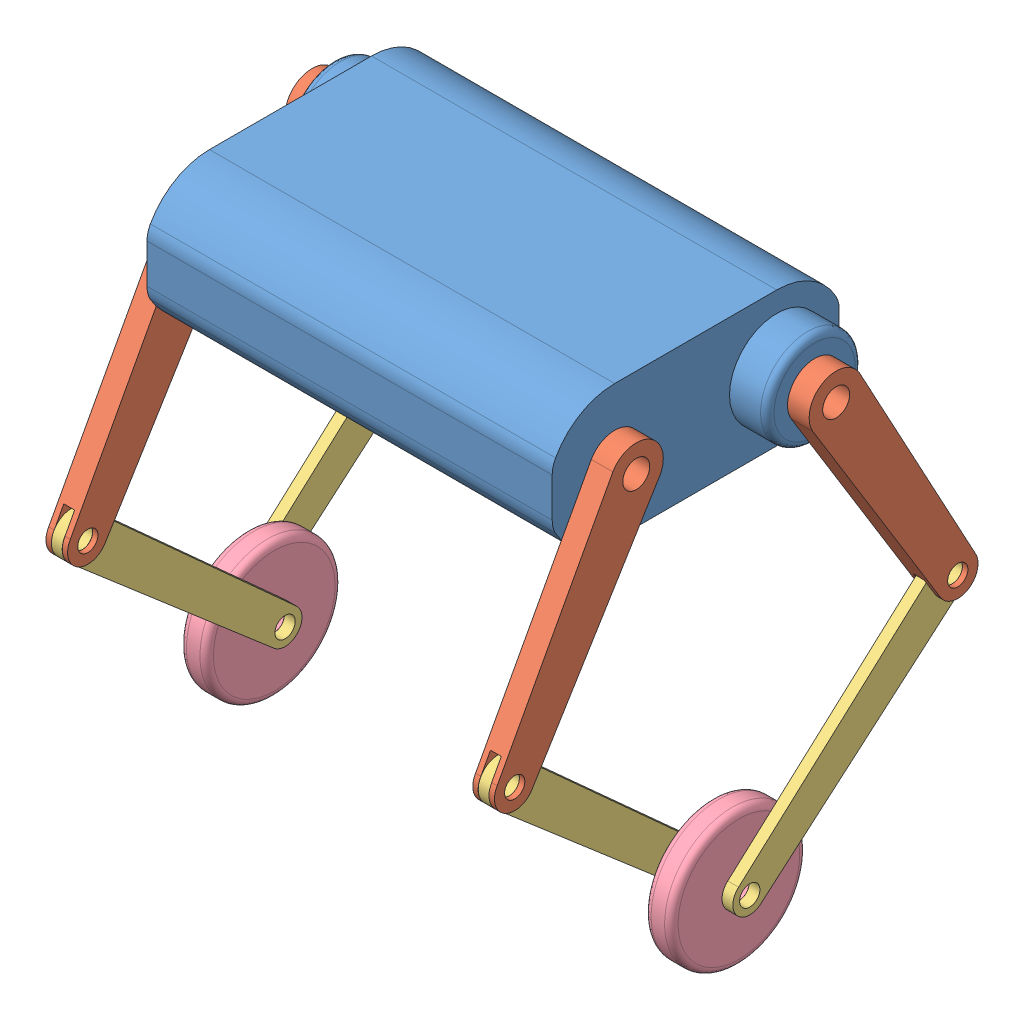
SolidWorks assembly 毕设轮足, configuration 默认. Lengths in mm.
Overall size (388 388.6 349.64).
12 component instances, 5 part files, 30 mates.
Components (placement in the parent):
- 机身-1: 机身 [默认] at (-112.6358 110.9969 -92.9782) size (356 100 212.5)
- 大腿-1: 大腿 [默认] at (187.3642 110.9969 -32.9782) x (1 0 0) z (0 0.5 0.866025) size (16 215 40)
- 大腿-2: 大腿 [默认] at (215.3642 110.9969 -152.9782) x (1 0 0) z (0 -0.5 0.866025) size (16 215 40)
- 小腿-1: 小腿 [默认] at (191.3642 -44.8877 57.0218) x (1 0 0) z (0 -0.75 0.661438) size (8 227.5 30)
- 小腿-2: 小腿 [默认] at (219.3642 -44.8877 -242.9782) x (1 0 0) z (0 0.75 0.661438) size (8 227.5 30)
- 车轮-1: 车轮 [默认] at (199.3642 -177.1752 -92.9782) x (1 0 0) z (0 -0.006127 0.999981) size (20 100 100)
- 大腿-3: 大腿 [默认] at (-112.6358 110.9969 -32.9782) x (-1 0 0) z (0 -0.5 -0.866025) size (16 215 40)
- 大腿-4: 大腿 [默认] at (-156.6358 110.9969 -152.9782) x (1 0 0) z (0 -0.5 0.866025) size (16 215 40)
- 小腿-3: 小腿 [默认] at (-116.6358 -44.8877 57.0218) x (-1 0 0) z (0 0.75 -0.661438) size (8 227.5 30)
- 小腿-4: 小腿 [默认] at (-144.6358 -44.8877 -242.9782) x (-1 0 0) z (0 -0.75 -0.661438) size (8 227.5 30)
- 车轮-2: 车轮 [默认] at (-124.6358 -177.1752 -92.9782) x (-1 0 0) z (0 0.999963 0.008584) size (20 100 100)
- 底板-1: 底板 [默认] at (37.3642 -247.1752 -92.9782) x (0 1 0) z (1 0 0) size (20 500 500) (hidden)
Mates (geometry in assembly coordinates):
- 重合1: coincident anti-aligned: plane of 机身-1 through (187.3642 110.9969 -92.9782) normal (1 0 0); plane of 大腿-1 through (187.3642 110.9969 -32.9782) normal (-1 0 0)
- 同心1: concentric anti-aligned: cylinder of 机身-1 through (187.3642 110.9969 -32.9782) axis (-1 0 0) radius 15; cylinder of 大腿-1 through (187.3642 110.9969 -32.9782) axis (1 0 0) radius 10
- 同心2: concentric anti-aligned: cylinder of 机身-1 through (187.3642 110.9969 -152.9782) axis (-1 0 0) radius 15; cylinder of 大腿-2 through (215.3642 110.9969 -152.9782) axis (1 0 0) radius 10
- 同心3: concentric aligned: cylinder of 大腿-1 through (187.3642 -44.8877 57.0218) axis (1 0 0) radius 7.5; cylinder of 小腿-1 through (189.3642 -44.8877 57.0218) axis (1 0 0) radius 7.5
- 宽度1: width aligned: plane of 大腿-1 through (203.3642 110.9969 -32.9782) normal (1 0 0); plane of 小腿-1 through (187.3642 110.9969 -32.9782) normal (-1 0 0); plane of 大腿-1 through (199.3642 -44.8877 57.0218) normal (1 0 0); plane of 小腿-1 through (191.3642 -44.8877 57.0218) normal (-1 0 0)
- 宽度2: width anti-aligned: plane of 大腿-2 through (231.3642 110.9969 -152.9782) normal (1 0 0); plane of 小腿-2 through (215.3642 110.9969 -152.9782) normal (-1 0 0); plane of 大腿-2 through (219.3642 -44.8877 -242.9782) normal (-1 0 0); plane of 小腿-2 through (227.3642 -44.8877 -242.9782) normal (1 0 0)
- 同心5: concentric aligned: cylinder of 大腿-2 through (215.3642 -44.8877 -242.9782) axis (1 0 0) radius 7.5; cylinder of 小腿-2 through (217.3642 -44.8877 -242.9782) axis (1 0 0) radius 7.5
- 距离1: distance = 20 mm anti-aligned: plane of 小腿-2 through (219.3642 -44.8877 -242.9782) normal (-1 0 0); plane of 小腿-1 through (199.3642 -44.8877 57.0218) normal (1 0 0)
- 同心6: concentric aligned: cylinder of 小腿-1 through (189.3642 -177.1752 -92.9782) axis (1 0 0) radius 7.5; cylinder of 小腿-2 through (217.3642 -177.1752 -92.9782) axis (1 0 0) radius 7.5
- 同心7: concentric anti-aligned: cylinder of 小腿-1 through (189.3642 -177.1752 -92.9782) axis (1 0 0) radius 7.5; cylinder of 车轮-1 through (219.3642 -177.1752 -92.9782) axis (-1 0 0) radius 50
- 重合2: coincident anti-aligned: plane of 小腿-1 through (199.3642 -44.8877 57.0218) normal (1 0 0); plane of 车轮-1 through (199.3642 -177.1752 -92.9782) normal (-1 0 0)
- 同心8: concentric aligned: cylinder of 大腿-3 through (-112.6358 -44.8877 57.0218) axis (-1 0 0) radius 7.5; cylinder of 小腿-3 through (-114.6358 -44.8877 57.0218) axis (-1 0 0) radius 7.5
- 宽度3: width aligned: plane of 大腿-3 through (-128.6358 110.9969 -32.9782) normal (-1 0 0); plane of 大腿-3 through (-112.6358 110.9969 -32.9782) normal (1 0 0); plane of 小腿-3 through (-124.6358 -44.8877 57.0218) normal (-1 0 0); plane of 小腿-3 through (-116.6358 -44.8877 57.0218) normal (1 0 0)
- 宽度4: width aligned: plane of 大腿-4 through (-140.6358 110.9969 -152.9782) normal (1 0 0); plane of 大腿-4 through (-156.6358 110.9969 -152.9782) normal (-1 0 0); plane of 小腿-4 through (-144.6358 -44.8877 -242.9782) normal (1 0 0); plane of 小腿-4 through (-152.6358 -44.8877 -242.9782) normal (-1 0 0)
- 同心9: concentric anti-aligned: cylinder of 大腿-4 through (-156.6358 -44.8877 -242.9782) axis (1 0 0) radius 7.5; cylinder of 小腿-4 through (-142.6358 -44.8877 -242.9782) axis (-1 0 0) radius 7.5
- 距离2: distance = 20 mm anti-aligned: plane of 小腿-4 through (-144.6358 -44.8877 -242.9782) normal (1 0 0); plane of 小腿-3 through (-124.6358 -44.8877 57.0218) normal (-1 0 0)
- 同心10: concentric aligned: cylinder of 小腿-3 through (-114.6358 -177.1752 -92.9782) axis (-1 0 0) radius 7.5; cylinder of 小腿-4 through (-142.6358 -177.1752 -92.9782) axis (-1 0 0) radius 7.5
- 同心11: concentric anti-aligned: cylinder of 小腿-3 through (-114.6358 -177.1752 -92.9782) axis (-1 0 0) radius 7.5; cylinder of 车轮-2 through (-144.6358 -177.1752 -92.9782) axis (1 0 0) radius 50
- 重合4: coincident anti-aligned: plane of 机身-1 through (-112.6358 110.9969 -92.9782) normal (-1 0 0); plane of 大腿-3 through (-112.6358 110.9969 -32.9782) normal (1 0 0)
- 同心12: concentric aligned: cylinder of 机身-1 through (187.3642 110.9969 -32.9782) axis (-1 0 0) radius 15; cylinder of 大腿-3 through (-112.6358 110.9969 -32.9782) axis (-1 0 0) radius 10
- 同心13: concentric anti-aligned: cylinder of 机身-1 through (187.3642 110.9969 -152.9782) axis (-1 0 0) radius 15; cylinder of 大腿-4 through (-156.6358 110.9969 -152.9782) axis (1 0 0) radius 10
- 重合6: coincident anti-aligned: plane of 小腿-4 through (-144.6358 -44.8877 -242.9782) normal (1 0 0); plane of 车轮-2 through (-144.6358 -177.1752 -92.9782) normal (-1 0 0)
- 同心18: concentric anti-aligned: cylinder of 车轮-1 through (219.3642 -177.1752 -92.9782) axis (-1 0 0) radius 50; cylinder of 车轮-2 through (-144.6358 -177.1752 -92.9782) axis (1 0 0) radius 50
- 平行1: parallel aligned: plane of 底板-1 through (37.3642 -227.1752 -92.9782) normal (0 1 0)
- 平行2: parallel aligned: plane of 机身-1 through (187.3642 160.9969 -92.9782) normal (0 1 0); plane of 底板-1 through (37.3642 -227.1752 -92.9782) normal (0 1 0)
- 宽度7: width anti-aligned: plane of 底板-1 through (287.3642 -227.1752 157.0218) normal (1 0 0); plane of 底板-1 through (-212.6358 -227.1752 157.0218) normal (-1 0 0); plane of 机身-1 through (-112.6358 110.9969 -92.9782) normal (-1 0 0); plane of 机身-1 through (187.3642 110.9969 -92.9782) normal (1 0 0)
- 相切1: tangent anti-aligned: cylinder of 车轮-2 through (-144.6358 -177.1752 -92.9782) axis (1 0 0) radius 50; plane of 底板-1 through (37.3642 -227.1752 -92.9782) normal (0 1 0)
- 宽度8: width anti-aligned: plane of 底板-1 through (-212.6358 -227.1752 157.0218) normal (0 0 1); plane of 底板-1 through (-212.6358 -227.1752 -342.9782) normal (0 0 -1); plane of 机身-1 through (187.3642 110.9969 -199.2275) normal (0 0 -1); plane of 机身-1 through (187.3642 110.9969 13.2711) normal (0 0 1)
- 宽度9: width: plane of 底板-1 through (-212.6358 -227.1752 157.0218) normal (0 0 1); plane of 底板-1 through (-212.6358 -227.1752 -342.9782) normal (0 0 -1); cylinder of 车轮-2 through (-144.6358 -177.1752 -92.9782) axis (1 0 0) radius 50
- 角度1: planar angle = 2.094395 rad aligned: line of 大腿-4 through (-140.6358 110.9969 -152.9782) axis (0 -0.866025 -0.5); line of 机身-1 through (-112.6358 160.9969 -152.9782) axis (0 0 1)
